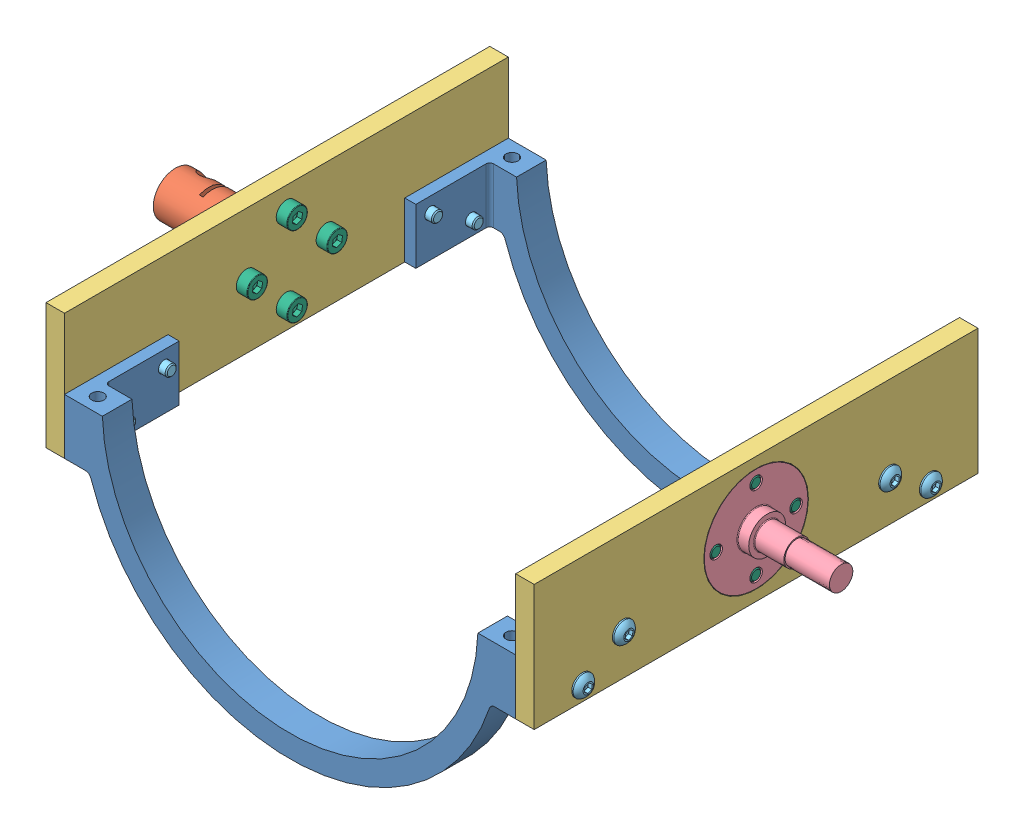
SolidWorks assembly Telescop Modeller Tray, configuration Default. Lengths in mm.
Overall size (180 73.9 120).
22 component instances, 6 part files, 47 mates.
Components (placement in the parent):
- Tube Clamp Bottom-1: Tube Clamp Bottom [Default] at (-77.0549 4.6143 -12.7507) x (0 0 1) z (1 0 0) size (28 54.9 122)
- Tube Clamp Bottom-2: Tube Clamp Bottom [Default] at (-77.0638 4.6143 -116.7507) x (0 0 -1) z (-1 0 0) size (28 54.9 122)
- Side2_Turned-1: Side2_Turned [Default] at (-138.0593 -12.2857 -4.7507) x (-1 0 0) z (0 0 -1) size (27.5 28 28)
- Side_Housing-1: Side_Housing [Default] at (-16.0593 -12.2857 -124.7507) size (5 34 120)
- Side1_Turned-1: Side1_Turned [Default] at (-16.0593 -12.2857 -124.7507) size (25.5 28 28)
- socket button head screw_iso-6: socket button head screw_iso [ISO 7380 - M3 x 10 --- 10N] at (-144.7093 -8.2857 -111.7507) size (11.65 5.7 5.7)
- socket button head screw_iso-7: socket button head screw_iso [ISO 7380 - M3 x 10 --- 10N] at (-144.7093 -1.2857 -100.7507) size (11.65 5.7 5.7)
- socket button head screw_iso-12: socket button head screw_iso [ISO 7380 - M3 x 10 --- 10N] at (-144.7093 -1.2857 -28.7507) size (11.65 5.7 5.7)
- socket button head screw_iso-13: socket button head screw_iso [ISO 7380 - M3 x 10 --- 10N] at (-144.7093 -8.2857 -17.7507) size (11.65 5.7 5.7)
- Side_Housing-2: Side_Housing [Default] at (-138.0593 -12.2857 -4.7507) x (-1 0 0) z (0 0 -1) size (5 34 120)
- socket head cap screw_iso-1: socket head cap screw_iso [ISO 4762 M3 x 5 --- 5N] at (-19.0593 15.5143 -64.7507) size (8 5.5 5.5)
- socket head cap screw_iso-2: socket head cap screw_iso [ISO 4762 M3 x 5 --- 5N] at (-19.0593 4.7143 -75.5507) size (8 5.5 5.5)
- socket head cap screw_iso-3: socket head cap screw_iso [ISO 4762 M3 x 5 --- 5N] at (-19.0593 -6.0857 -64.7507) size (8 5.5 5.5)
- socket head cap screw_iso-4: socket head cap screw_iso [ISO 4762 M3 x 5 --- 5N] at (-19.0593 4.7143 -53.9507) size (8 5.5 5.5)
- socket head cap screw_iso-9: socket head cap screw_iso [ISO 4762 M3 x 5 - 5N] at (-135.0593 4.7143 -75.5507) x (-1 0 0) z (0 0.924225 0.381849) size (8 5.5 5.5)
- socket head cap screw_iso-10: socket head cap screw_iso [ISO 4762 M3 x 5 - 5N] at (-135.0593 15.5143 -64.7507) x (-1 0 0) z (0 0.924225 0.381849) size (8 5.5 5.5)
- socket head cap screw_iso-11: socket head cap screw_iso [ISO 4762 M3 x 5 - 5N] at (-135.0593 4.7143 -53.9507) x (-1 0 0) z (0 0.924225 0.381849) size (8 5.5 5.5)
- socket head cap screw_iso-12: socket head cap screw_iso [ISO 4762 M3 x 5 - 5N] at (-135.0593 -6.0857 -64.7507) x (-1 0 0) z (0 0.924225 0.381849) size (8 5.5 5.5)
- socket button head screw_iso-25: socket button head screw_iso [ISO 7380 - M3 x 10 - 10N] at (-9.4093 -8.2857 -111.7507) x (-1 0 0) z (0 0.924225 0.381849) size (11.65 5.7 5.7)
- socket button head screw_iso-26: socket button head screw_iso [ISO 7380 - M3 x 10 - 10N] at (-9.4093 -1.2857 -100.7507) x (-1 0 0) z (0 0.924225 0.381849) size (11.65 5.7 5.7)
- socket button head screw_iso-27: socket button head screw_iso [ISO 7380 - M3 x 10 - 10N] at (-9.4093 -1.2857 -28.7507) x (-1 0 0) z (0 0.924225 0.381849) size (11.65 5.7 5.7)
- socket button head screw_iso-28: socket button head screw_iso [ISO 7380 - M3 x 10 - 10N] at (-9.4093 -8.2857 -17.7507) x (-1 0 0) z (0 0.924225 0.381849) size (11.65 5.7 5.7)
Mates (geometry in assembly coordinates):
- Coincident9: coincident aligned: plane of Tube Clamp Bottom-1 through (-132.3751 -13.7857 -4.7507) normal (0 0 1); plane of Side_Housing-1 through (-11.0593 -12.2857 -4.7507) normal (0 0 1)
- Coincident10: coincident aligned: plane of Tube Clamp Bottom-1 through (-16.0593 -12.2857 -4.7507) normal (0 -1 0); plane of Side_Housing-1 through (-11.0593 -12.2857 -124.7507) normal (0 -1 0)
- Coincident11: coincident anti-aligned: plane of Tube Clamp Bottom-1 through (-16.0593 2.7143 -4.7507) normal (1 0 0); plane of Side_Housing-1 through (-16.0593 -12.2857 -124.7507) normal (-1 0 0)
- Concentric3: concentric anti-aligned: cylinder of Side_Housing-1 through (-13.5593 4.7143 -64.7507) axis (1 0 0) radius 14.15; cylinder of Side1_Turned-1 through (11.9407 4.7143 -64.7507) axis (-1 0 0) radius 3.5
- Concentric4: concentric aligned: cylinder of Side_Housing-1 through (-13.5593 15.5143 -64.7507) axis (1 0 0) radius 1.7; cylinder of Side1_Turned-1 through (-11.0593 15.5143 -64.7507) axis (1 0 0) radius 1.7
- Coincident15: coincident anti-aligned: plane of Side_Housing-1 through (-13.5593 -12.2857 -124.7507) normal (1 0 0); plane of Side1_Turned-1 through (-13.5593 -12.2857 -50.7507) normal (-1 0 0)
- Coincident17: coincident anti-aligned: plane of Tube Clamp Bottom-2 through (-16.0593 2.7143 -124.7507) normal (1 0 0); plane of Side_Housing-1 through (-16.0593 -12.2857 -124.7507) normal (-1 0 0)
- Coincident18: coincident aligned: plane of Tube Clamp Bottom-2 through (-21.7435 -13.7857 -124.7507) normal (0 0 -1); plane of Side_Housing-1 through (-11.0593 -12.2857 -124.7507) normal (0 0 -1)
- Coincident19: coincident aligned: plane of Tube Clamp Bottom-1 through (-16.0593 2.7143 -4.7507) normal (0 1 0); plane of Tube Clamp Bottom-2 through (-26.2993 2.7143 -124.7507) normal (0 1 0)
- Coincident69: coincident aligned: plane of Tube Clamp Bottom-1 through (-132.3751 -13.7857 -4.7507) normal (0 0 1); plane of Side_Housing-2 through (-143.0593 -12.2857 -4.7507) normal (0 0 1)
- Coincident70: coincident aligned: plane of Tube Clamp Bottom-1 through (-138.0593 -12.2857 -4.7507) normal (0 -1 0); plane of Side_Housing-2 through (-143.0593 -12.2857 -4.7507) normal (0 -1 0)
- Coincident71: coincident anti-aligned: plane of Tube Clamp Bottom-1 through (-138.0593 2.7143 -4.7507) normal (-1 0 0); plane of Side_Housing-2 through (-138.0593 -12.2857 -4.7507) normal (1 0 0)
- Concentric51: concentric aligned: cylinder of Side2_Turned-1 through (-133.0593 4.7143 -64.7507) axis (-1 0 0) radius 14; cylinder of Side_Housing-2 through (-140.5593 4.7143 -64.7507) axis (-1 0 0) radius 14.15
- Concentric52: concentric aligned: cylinder of Side2_Turned-1 through (-143.0593 15.5143 -64.7507) axis (-1 0 0) radius 1.7; cylinder of Side_Housing-2 through (-140.5593 15.5143 -64.7507) axis (-1 0 0) radius 1.7
- Coincident81: coincident anti-aligned: plane of Side2_Turned-1 through (-140.5593 -9.2857 -50.7507) normal (1 0 0); plane of Side_Housing-2 through (-140.5593 -12.2857 -4.7507) normal (-1 0 0)
- Coincident82: coincident aligned: plane of socket button head screw_iso-12 through (-143.0593 0.2143 -28.7507) normal (1 0 0); plane of socket button head screw_iso-13 through (-143.0593 -6.7857 -17.7507) normal (1 0 0)
- Concentric53: concentric anti-aligned: cylinder of socket button head screw_iso-13 through (-144.7093 -8.2857 -17.7507) axis (-1 0 0) radius 1.5; cylinder of Side_Housing-2 through (-138.0593 -8.2857 -17.7507) axis (1 0 0) radius 1.7
- Concentric54: concentric anti-aligned: cylinder of socket button head screw_iso-12 through (-144.7093 -1.2857 -28.7507) axis (-1 0 0) radius 1.5; cylinder of Side_Housing-2 through (-138.0593 -1.2857 -28.7507) axis (1 0 0) radius 1.7
- Coincident83: coincident anti-aligned: plane of socket button head screw_iso-12 through (-143.0593 0.2143 -28.7507) normal (1 0 0); plane of Side_Housing-2 through (-143.0593 -12.2857 -4.7507) normal (-1 0 0)
- Coincident84: coincident aligned: plane of socket button head screw_iso-6 through (-143.0593 -6.7857 -111.7507) normal (1 0 0); plane of socket button head screw_iso-7 through (-143.0593 0.2143 -100.7507) normal (1 0 0)
- Concentric55: concentric anti-aligned: cylinder of socket button head screw_iso-7 through (-144.7093 -1.2857 -100.7507) axis (-1 0 0) radius 1.5; cylinder of Side_Housing-2 through (-138.0593 -1.2857 -100.7507) axis (1 0 0) radius 1.7
- Concentric56: concentric anti-aligned: cylinder of socket button head screw_iso-6 through (-144.7093 -8.2857 -111.7507) axis (-1 0 0) radius 1.5; cylinder of Side_Housing-2 through (-138.0593 -8.2857 -111.7507) axis (1 0 0) radius 1.7
- Coincident85: coincident anti-aligned: plane of socket button head screw_iso-6 through (-143.0593 -6.7857 -111.7507) normal (1 0 0); plane of Side_Housing-2 through (-143.0593 -12.2857 -4.7507) normal (-1 0 0)
- Concentric57: concentric anti-aligned: cylinder of Side_Housing-1 through (-13.5593 15.5143 -64.7507) axis (1 0 0) radius 1.7; cylinder of socket head cap screw_iso-1 through (-50.8093 15.5143 -64.7507) axis (-1 0 0) radius 2.75
- Coincident86: coincident anti-aligned: plane of Side_Housing-1 through (-16.0593 -12.2857 -124.7507) normal (-1 0 0); plane of socket head cap screw_iso-1 through (-16.0593 18.2643 -64.7507) normal (1 0 0)
- Concentric58: concentric anti-aligned: cylinder of Side_Housing-1 through (-13.5593 4.7143 -75.5507) axis (1 0 0) radius 1.7; cylinder of socket head cap screw_iso-2 through (-50.8093 4.7143 -75.5507) axis (-1 0 0) radius 2.75
- Coincident87: coincident anti-aligned: plane of Side_Housing-1 through (-16.0593 -12.2857 -124.7507) normal (-1 0 0); plane of socket head cap screw_iso-2 through (-16.0593 7.4643 -75.5507) normal (1 0 0)
- Concentric59: concentric anti-aligned: cylinder of Side_Housing-1 through (-13.5593 -6.0857 -64.7507) axis (1 0 0) radius 1.7; cylinder of socket head cap screw_iso-3 through (-50.8093 -6.0857 -64.7507) axis (-1 0 0) radius 2.75
- Coincident88: coincident anti-aligned: plane of Side_Housing-1 through (-16.0593 -12.2857 -124.7507) normal (-1 0 0); plane of socket head cap screw_iso-3 through (-16.0593 -3.3357 -64.7507) normal (1 0 0)
- Concentric60: concentric anti-aligned: cylinder of Side_Housing-1 through (-13.5593 4.7143 -53.9507) axis (1 0 0) radius 1.7; cylinder of socket head cap screw_iso-4 through (-50.8093 4.7143 -53.9507) axis (-1 0 0) radius 2.75
- Coincident89: coincident anti-aligned: plane of Side_Housing-1 through (-16.0593 -12.2857 -124.7507) normal (-1 0 0); plane of socket head cap screw_iso-4 through (-16.0593 7.4643 -53.9507) normal (1 0 0)
- Concentric61: concentric anti-aligned: cylinder of Side_Housing-2 through (-140.5593 4.7143 -75.5507) axis (-1 0 0) radius 1.7; cylinder of socket head cap screw_iso-9 through (-103.3093 4.7143 -75.5507) axis (1 0 0) radius 2.75
- Coincident90: coincident anti-aligned: plane of Side_Housing-2 through (-138.0593 -12.2857 -4.7507) normal (1 0 0); plane of socket head cap screw_iso-9 through (-138.0593 3.6642 -73.0091) normal (-1 0 0)
- Concentric62: concentric anti-aligned: cylinder of Side_Housing-2 through (-140.5593 15.5143 -64.7507) axis (-1 0 0) radius 1.7; cylinder of socket head cap screw_iso-10 through (-103.3093 15.5143 -64.7507) axis (1 0 0) radius 2.75
- Coincident91: coincident anti-aligned: plane of Side_Housing-2 through (-138.0593 -12.2857 -4.7507) normal (1 0 0); plane of socket head cap screw_iso-10 through (-138.0593 14.4642 -62.2091) normal (-1 0 0)
- Concentric63: concentric anti-aligned: cylinder of Side_Housing-2 through (-140.5593 4.7143 -53.9507) axis (-1 0 0) radius 1.7; cylinder of socket head cap screw_iso-11 through (-103.3093 4.7143 -53.9507) axis (1 0 0) radius 2.75
- Coincident92: coincident anti-aligned: plane of Side_Housing-2 through (-138.0593 -12.2857 -4.7507) normal (1 0 0); plane of socket head cap screw_iso-11 through (-138.0593 3.6642 -51.4091) normal (-1 0 0)
- Concentric64: concentric anti-aligned: cylinder of Side_Housing-2 through (-140.5593 -6.0857 -64.7507) axis (-1 0 0) radius 1.7; cylinder of socket head cap screw_iso-12 through (-103.3093 -6.0857 -64.7507) axis (1 0 0) radius 2.75
- Coincident93: coincident anti-aligned: plane of Side_Housing-2 through (-138.0593 -12.2857 -4.7507) normal (1 0 0); plane of socket head cap screw_iso-12 through (-138.0593 -7.1358 -62.2091) normal (-1 0 0)
- Concentric66: concentric anti-aligned: cylinder of Side_Housing-1 through (-16.0593 -8.2857 -111.7507) axis (-1 0 0) radius 1.7; cylinder of socket button head screw_iso-25 through (-9.4093 -8.2857 -111.7507) axis (1 0 0) radius 2.85
- Coincident95: coincident anti-aligned: plane of Side_Housing-1 through (-11.0593 -12.2857 -124.7507) normal (1 0 0); plane of socket button head screw_iso-25 through (-11.0593 -8.8585 -110.3644) normal (-1 0 0)
- Concentric67: concentric anti-aligned: cylinder of Side_Housing-1 through (-16.0593 -1.2857 -100.7507) axis (-1 0 0) radius 1.7; cylinder of socket button head screw_iso-26 through (-9.4093 -1.2857 -100.7507) axis (1 0 0) radius 2.85
- Coincident96: coincident anti-aligned: plane of Side_Housing-1 through (-11.0593 -12.2857 -124.7507) normal (1 0 0); plane of socket button head screw_iso-26 through (-11.0593 -1.8585 -99.3644) normal (-1 0 0)
- Concentric68: concentric anti-aligned: cylinder of Side_Housing-1 through (-16.0593 -1.2857 -28.7507) axis (-1 0 0) radius 1.7; cylinder of socket button head screw_iso-27 through (-9.4093 -1.2857 -28.7507) axis (1 0 0) radius 2.85
- Coincident97: coincident anti-aligned: plane of Side_Housing-1 through (-11.0593 -12.2857 -124.7507) normal (1 0 0); plane of socket button head screw_iso-27 through (-11.0593 -1.8585 -27.3644) normal (-1 0 0)
- Concentric69: concentric anti-aligned: cylinder of Side_Housing-1 through (-16.0593 -8.2857 -17.7507) axis (-1 0 0) radius 1.7; cylinder of socket button head screw_iso-28 through (-9.4093 -8.2857 -17.7507) axis (1 0 0) radius 2.85
- Coincident98: coincident anti-aligned: plane of Side_Housing-1 through (-11.0593 -12.2857 -124.7507) normal (1 0 0); plane of socket button head screw_iso-28 through (-11.0593 -8.8585 -16.3644) normal (-1 0 0)
